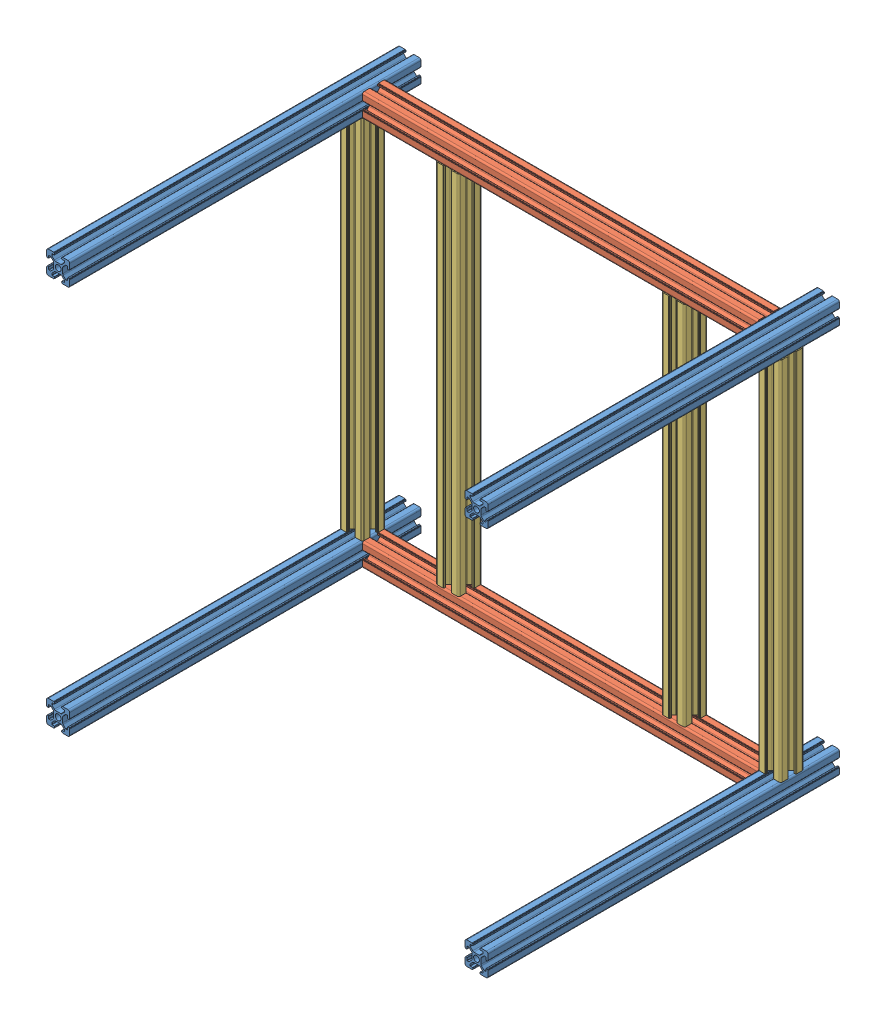
SolidWorks assembly Stand subassembly, configuration Default. Lengths in mm.
Overall size (382.9 357.51 304.8).
10 component instances, 3 part files, 28 mates.
Components (placement in the parent):
- Aluminum 20mm t slot 12 in vertical-1: Aluminum 20mm t slot 12 in vertical [Default] at (136.1777 212.364 95.9394) size (20 20 304.8)
- Aluminum 20mm t slot 12 in vertical-2: Aluminum 20mm t slot 12 in vertical [Default] at (499.0786 212.3655 95.9394) size (20 20 304.8)
- Aluminum 20mm t slot 13.5in-1: Aluminum 20mm t slot 13.5in [Default] at (146.1784 212.364 136.7392) x (0 0 -1) z (1 0 0) size (20 20 342.9)
- Aluminum 20mm t slot 13.5in-3: Aluminum 20mm t slot 13.5in [Default] at (146.1768 549.8664 136.7376) x (0 0 -1) z (1 0 0) size (20 20 342.9)
- Aluminum 20mm t slot 12 in vertical-5: Aluminum 20mm t slot 12 in vertical [Default] at (499.077 549.8679 95.9378) size (20 20 304.8)
- Aluminum 20mm t slot 12 in vertical-6: Aluminum 20mm t slot 12 in vertical [Default] at (136.1762 549.8664 95.9378) size (20 20 304.8)
- Aluminum 20mm t slot 12.5in-1: Aluminum 20mm t slot 12.5in [Default] at (499.0786 222.3667 136.7382) x (1 0 0) z (0 1 0) size (20 20 317.5)
- Aluminum 20mm t slot 12.5in-2: Aluminum 20mm t slot 12.5in [Default] at (136.1777 222.3652 136.7382) x (1 0 0) z (0 1 0) size (20 20 317.5)
- Aluminum 20mm t slot 12.5in-3: Aluminum 20mm t slot 12.5in [Default] at (219.6786 222.3652 136.7382) x (1 0 0) z (0 1 0) size (20 20 317.5)
- Aluminum 20mm t slot 12.5in-4: Aluminum 20mm t slot 12.5in [Default] at (415.5777 222.3652 136.7382) x (1 0 0) z (0 1 0) size (20 20 317.5)
Mates (geometry in assembly coordinates):
- Coincident3: coincident anti-aligned: plane of Aluminum 20mm t slot 15 in-2 through (489.0784 212.3655 400.7394) normal (-1 0 0); plane of Aluminum 20mm t slot 13in-1 through (489.0784 212.364 136.7392) normal (1 0 0)
- Distance1: distance = 254 mm: line of Aluminum 20mm t slot 13in-1 through (146.1784 220.8636 146.7394) axis (0 -1 0); line of Aluminum 20mm t slot 15 in-1 through (146.1784 220.8652 400.7394) axis (0 -1 0)
- Coincident6: coincident: line of Aluminum 20mm t slot 15 in-1 through (146.1784 220.8652 400.7394) axis (0 0 -1); point of Aluminum 20mm t slot 13in-1
- Coincident7: coincident: line of Aluminum 20mm t slot 15 in-2 through (489.0784 220.8652 400.7394) axis (0 0 -1); point of Aluminum 20mm t slot 13in-1
- Parallel2: parallel anti-aligned: line of Aluminum 20mm t slot 15 in-2 through (490.5784 222.3652 400.7394) axis (0 0 -1); line of Aluminum 20mm t slot 13in-1 through (489.0784 222.3652 128.2386) axis (0 0 1)
- Distance2: distance = 254 mm: line of Aluminum 20mm t slot 15 in-2 through (489.0784 220.8652 400.7394) axis (0 -1 0); plane of Aluminum 20mm t slot 13in-1 through (489.0784 212.364 146.7394) normal (0 0 1)
- Coincident10: coincident anti-aligned: plane of Aluminum 20mm t slot 13in-3 through (489.0768 549.8664 136.7376) normal (1 0 0); plane of Aluminum 20mm t slot 15 in-5 through (489.0768 549.8679 400.7378) normal (-1 0 0)
- Coincident11: coincident anti-aligned: plane of Aluminum 20mm t slot 13in-3 through (146.1768 549.8664 136.7376) normal (-1 0 0); plane of Aluminum 20mm t slot 15 in-6 through (146.1768 549.8664 400.7378) normal (1 0 0)
- Distance3: distance = 254 mm: line of Aluminum 20mm t slot 13in-3 through (146.1768 558.366 146.7378) axis (0 -1 0); line of Aluminum 20mm t slot 15 in-6 through (146.1768 558.3676 400.7378) axis (0 -1 0)
- Coincident12: coincident: point of Aluminum 20mm t slot 13in-3; line of Aluminum 20mm t slot 15 in-6 through (146.1768 558.3676 400.7378) axis (0 0 -1)
- Coincident13: coincident: point of Aluminum 20mm t slot 13in-3; line of Aluminum 20mm t slot 15 in-5 through (489.0768 558.3676 400.7378) axis (0 0 -1)
- Parallel3: parallel anti-aligned: line of Aluminum 20mm t slot 13in-3 through (489.0768 559.8676 128.237) axis (0 0 1); line of Aluminum 20mm t slot 15 in-5 through (490.5768 559.8676 400.7378) axis (0 0 -1)
- Distance4: distance = 254 mm: line of Aluminum 20mm t slot 15 in-5 through (489.0768 558.3676 400.7378) axis (0 -1 0); plane of Aluminum 20mm t slot 13in-3 through (489.0768 549.8664 146.7378) normal (0 0 1)
- Coincident14: coincident anti-aligned: plane of Aluminum 20mm t slot 15 in-2 through (499.0786 222.3667 400.7394) normal (0 1 0); plane of Aluminum 20mm t slot 12in-1 through (499.0786 222.3667 136.7382) normal (0 -1 0)
- Coincident15: coincident: line of Aluminum 20mm t slot 15 in-2 through (507.5792 222.3667 400.7394) axis (0 0 -1); point of Aluminum 20mm t slot 12in-1
- Parallel4: parallel anti-aligned: line of Aluminum 20mm t slot 15 in-2 through (509.0792 220.8667 400.7394) axis (0 0 -1); line of Aluminum 20mm t slot 12in-1 through (509.0792 222.3667 128.237) axis (0 0 1)
- Distance5: distance = 254 mm: plane of Aluminum 20mm t slot 12in-1 through (499.0786 539.8667 146.7394) normal (0 0 1); line of Aluminum 20mm t slot 15 in-2 through (490.5784 222.3652 400.7394) axis (1 0 0)
- Coincident22: coincident anti-aligned: plane of Aluminum 20mm t slot 15 in-5 through (499.077 539.8667 400.7378) normal (0 -1 0); plane of Aluminum 20mm t slot 12in-1 through (499.0786 539.8667 136.7382) normal (0 1 0)
- Coincident23: coincident: line of Aluminum 20mm t slot 15 in-5 through (490.5784 539.8667 400.7378) axis (0 0 -1); point of Aluminum 20mm t slot 12in-1
- Distance6: distance = 254 mm: line of Aluminum 20mm t slot 12in-1 through (507.5808 539.8667 146.7378) axis (-1 0 0); line of Aluminum 20mm t slot 15 in-5 through (507.5792 539.8683 400.7378) axis (-1 0 0)
- Coincident24: coincident anti-aligned: plane of Aluminum 20mm t slot 15 in-1 through (136.1777 222.3652 400.7394) normal (0 1 0); plane of Aluminum 20mm t slot 12in-2 through (136.1777 222.3652 136.7382) normal (0 -1 0)
- Distance7: distance = 254 mm: line of Aluminum 20mm t slot 12in-2 through (127.6791 222.3652 146.7394) axis (1 0 0); line of Aluminum 20mm t slot 15 in-1 through (127.6775 222.3636 400.7394) axis (1 0 0)
- Coincident28: coincident anti-aligned: plane of Aluminum 20mm t slot 13in-1 through (489.0784 222.3652 136.7392) normal (0 1 0); plane of Aluminum 20mm t slot 12in-3 through (219.6786 222.3652 136.7382) normal (0 -1 0)
- Coincident29: coincident: line of Aluminum 20mm t slot 13in-1 through (489.0784 222.3652 132.8586) axis (-1 0 0); point of Aluminum 20mm t slot 12in-3
- Distance8: distance = 63.5 mm: line of Aluminum 20mm t slot 12in-3 through (209.6784 222.3652 128.2386) axis (0 0 1); line of Aluminum 20mm t slot 13in-1 through (146.1784 222.3652 128.2386) axis (0 0 1)
- Coincident31: coincident anti-aligned: plane of Aluminum 20mm t slot 13in-1 through (489.0784 222.3652 136.7392) normal (0 1 0); plane of Aluminum 20mm t slot 12in-4 through (377.4777 222.3652 136.7382) normal (0 -1 0)
- Coincident32: coincident: line of Aluminum 20mm t slot 13in-1 through (489.0784 222.3652 132.8586) axis (-1 0 0); point of Aluminum 20mm t slot 12in-4
- Distance9: distance = 63.5 mm: line of Aluminum 20mm t slot 12in-4 through (425.5784 222.3652 128.237) axis (0 0 1); line of Aluminum 20mm t slot 12in-1 through (489.0784 222.3667 128.2386) axis (0 0 1)
